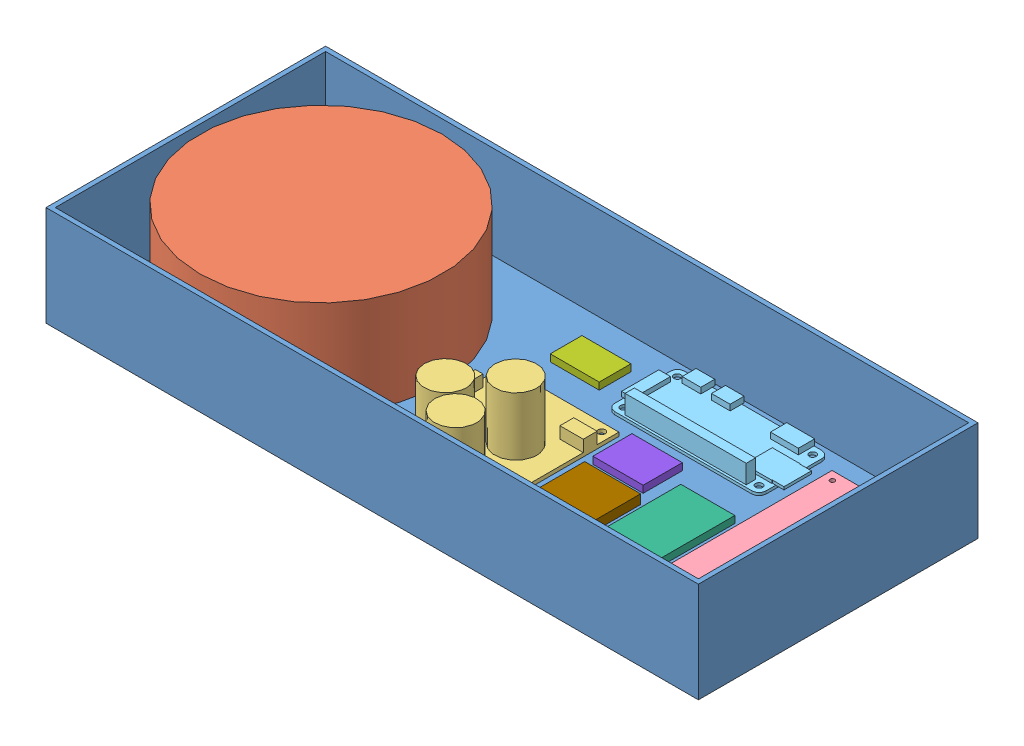
SolidWorks assembly AMP, configuration Default. Lengths in mm.
Overall size (280 44 120).
9 component instances, 9 part files, 11 mates.
Components (placement in the parent):
- AMPBox-1: AMPBox [Default] at (-21.6961 94.2529 66.7671) size (280 43 120)
- _transformer-1: _transformer [Default] at (37.0307 97.2529 127.4552) size (104 41 104)
- _AMP_POWER-1: _AMP_POWER [Default] at (97.2039 97.2529 178.496) x (0 0 -1) z (1 0 0) size (69.6 26.6 49.1)
- _AMP-1: _AMP [Default] at (206.3039 97.2529 174.7042) x (0 0 -1) z (1 0 0) size (97.3 21.6 47)
- _raspberrypizero-1: _raspberrypizero [Default] at (199.3213 97.2529 101.7671) x (-1 0 0) z (0 0 -1) size (69.5 9.2 31)
- _miniDSP-1: _miniDSP [Default] at (180.375 97.2529 116.3895) size (23.2 3 42.3)
- _miniPOWER-1: _miniPOWER [Default] at (103.8916 97.2529 82.3306) size (21 3 13.6)
- _miniDAC-1: _miniDAC [Default] at (152.984 99.1674 109.9533) size (21.6 3 16.8)
- _BT-1: _BT [Default] at (176.3039 97.2529 129.5842) x (0 0 1) z (-1 0 0) size (38 4 24)
Mates (geometry in assembly coordinates):
- Coincident1: coincident anti-aligned: plane of AMPBox-1 through (-21.6961 97.2529 66.7671) normal (0 1 0); plane of _transformer-1 through (37.0307 97.2529 127.4552) normal (0 -1 0)
- Coincident2: coincident anti-aligned: plane of AMPBox-1 through (-21.6961 97.2529 66.7671) normal (0 1 0); plane of _AMP_POWER-1 through (97.2039 97.2529 178.496) normal (0 -1 0)
- Coincident3: coincident anti-aligned: plane of AMPBox-1 through (-21.6961 97.2529 66.7671) normal (0 1 0); plane of _AMP-1 through (206.3039 97.2529 174.7042) normal (0 -1 0)
- Coincident4: coincident anti-aligned: plane of AMPBox-1 through (-21.6961 97.2529 66.7671) normal (0 1 0); plane of _raspberrypizero-1 through (199.3213 97.2529 101.7671) normal (0 -1 0)
- Coincident5: coincident anti-aligned: plane of AMPBox-1 through (-21.6961 97.2529 66.7671) normal (0 1 0); plane of _miniDSP-1 through (180.375 97.2529 116.3895) normal (0 -1 0)
- Distance3: distance = 5 mm aligned: plane of AMPBox-1 through (258.3039 97.2529 66.7671) normal (1 0 0); plane of _AMP-1 through (253.3039 98.8529 174.7042) normal (1 0 0)
- Distance2: distance = 5 mm: plane of AMPBox-1 through (-21.6961 97.2529 66.7671) normal (0 0 -1); line of _raspberrypizero-1 through (196.3213 97.2529 71.7671) axis (-1 0 0)
- Distance4: distance = 110 mm anti-aligned: plane of _AMP_POWER-1 through (146.3039 98.8529 178.496) normal (1 0 0); plane of AMPBox-1 through (256.3039 137.2529 68.7671) normal (-1 0 0)
- Coincident6: coincident anti-aligned: plane of AMPBox-1 through (-21.6961 97.2529 66.7671) normal (0 1 0); plane of _miniPOWER-1 through (103.8916 97.2529 82.3306) normal (0 -1 0)
- Coincident7: coincident anti-aligned: plane of AMPBox-1 through (-21.6961 97.2529 66.7671) normal (0 1 0); plane of _BT-1 through (176.3039 97.2529 129.5842) normal (0 -1 0)
- Distance5: distance = 80 mm anti-aligned: plane of _BT-1 through (176.3039 101.2529 129.5842) normal (1 0 0); plane of AMPBox-1 through (256.3039 137.2529 68.7671) normal (-1 0 0)
